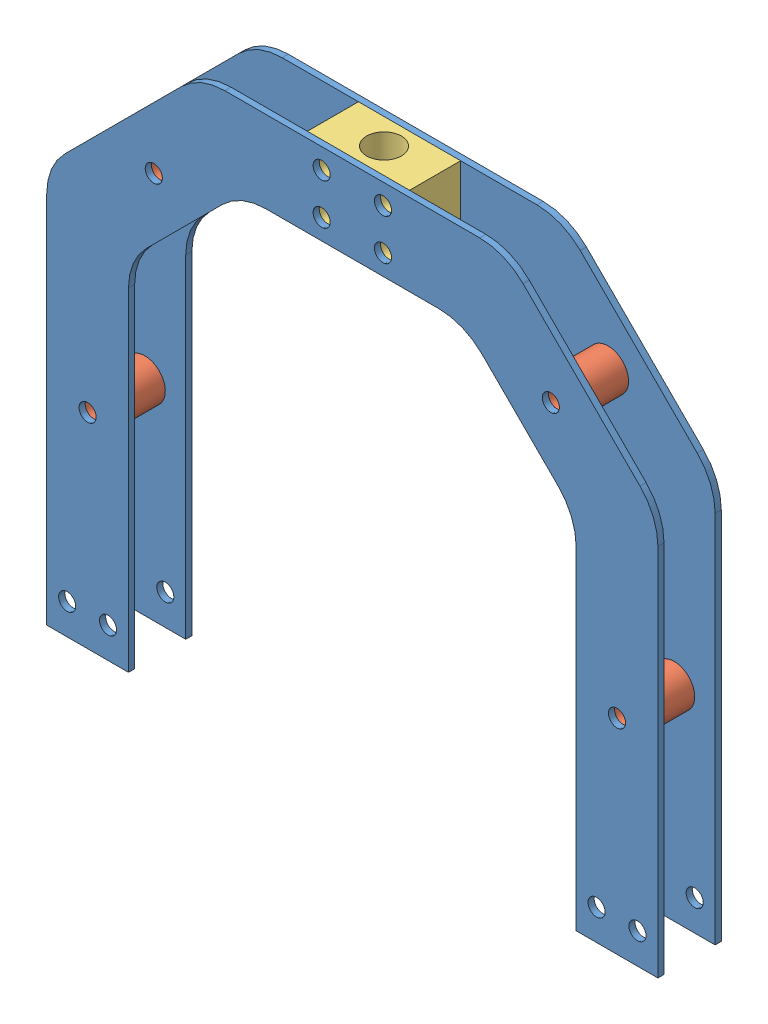
SolidWorks assembly Ensamblaje1, configuration Predeterminado. Lengths in mm.
Overall size (299 270 31).
7 component instances, 3 part files, 14 mates.
Components (placement in the parent):
- arco-1: arco [Predeterminado] at origin size (299 270 3)
- arco-2: arco [Predeterminado] at (0 0 28) size (299 270 3)
- virlo-1: virlo [Predeterminado] at (-129.5 100.125 3) x (0.157699 0.987487 0) z (0 0 1) size (20 20 25)
- virlo-2: virlo [Predeterminado] at (-97.125 217.625 3) size (20 20 25)
- virlo-3: virlo [Predeterminado] at (97.125 217.625 3) size (20 20 25)
- virlo-4: virlo [Predeterminado] at (129.5 100.125 3) size (20 20 25)
- bloque-1: bloque [Predeterminado] at (0 250 15.5) size (50 40 25)
Mates (geometry in assembly coordinates):
- Concéntrica1: concentric: cylinder of arco-1 through (-129.5 100.125 3) axis (0 0 1) radius 4.2; cylinder of virlo-1 through (-129.5 100.125 28) axis (0 0 1) radius 4.2
- Coincidente1: coincident anti-aligned: plane of arco-1 through (119.5 182.8236 3) normal (0 0 1); plane of virlo-1 through (-129.5 100.125 3) normal (0 0 -1)
- Concéntrica2: concentric: cylinder of arco-1 through (-97.125 217.625 3) axis (0 0 1) radius 4.2; cylinder of virlo-2 through (-97.125 217.625 28) axis (0 0 1) radius 4.2
- Coincidente2: coincident anti-aligned: plane of arco-1 through (119.5 182.8236 3) normal (0 0 1); plane of virlo-2 through (-97.125 217.625 3) normal (0 0 -1)
- Concéntrica3: concentric: cylinder of arco-1 through (97.125 217.625 3) axis (0 0 1) radius 4.2; cylinder of virlo-3 through (97.125 217.625 28) axis (0 0 1) radius 4.2
- Coincidente3: coincident anti-aligned: plane of arco-1 through (119.5 182.8236 3) normal (0 0 1); plane of virlo-3 through (97.125 217.625 3) normal (0 0 -1)
- Coincidente4: coincident anti-aligned: plane of arco-1 through (119.5 182.8236 3) normal (0 0 1); plane of virlo-4 through (129.5 100.125 3) normal (0 0 -1)
- Concéntrica4: concentric aligned: cylinder of arco-1 through (129.5 100.125 3) axis (0 0 1) radius 4.2; cylinder of virlo-4 through (129.5 100.125 28) axis (0 0 1) radius 4.2
- Coincidente5: coincident anti-aligned: plane of arco-1 through (119.5 182.8236 3) normal (0 0 1); plane of bloque-1 through (0 250 3) normal (0 0 -1)
- Concéntrica5: concentric aligned: cylinder of arco-1 through (-15 260 3) axis (0 0 1) radius 4.2; cylinder of bloque-1 through (-15 260 28) axis (0 0 1) radius 4.2
- Concéntrica6: concentric aligned: cylinder of arco-1 through (15 240 3) axis (0 0 1) radius 4.2; cylinder of bloque-1 through (15 240 28) axis (0 0 1) radius 4.2
- Coincidente6: coincident anti-aligned: plane of arco-2 through (119.5 182.8236 28) normal (0 0 -1); plane of bloque-1 through (0 250 28) normal (0 0 1)
- Coincidente7: coincident aligned: circle of arco-2; cylinder of bloque-1 through (-15 260 28) axis (0 0 1) radius 4.2
- Coincidente8: coincident aligned: circle of arco-2; cylinder of virlo-4 through (129.5 100.125 28) axis (0 0 1) radius 4.2
